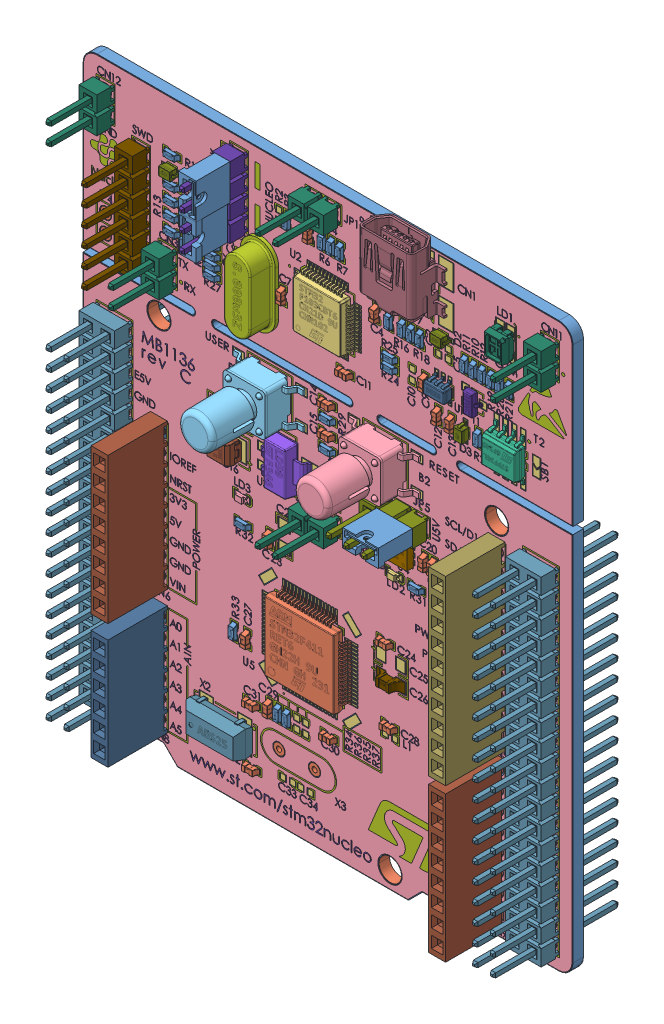
SolidWorks assembly NUCLEO-F411RE.STEP, configuration Défaut. Lengths in mm.
Overall size (70 83.97 20.27).
104 component instances, 40 part files, 0 mates.
Components (placement in the parent):
- NUCLEO-F411RE_PCB_Varsay_lan.STEP-1: NUCLEO-F411RE_PCB_Varsay_lan.STEP [Défaut] at origin size (70 82.5 1.5)
- NUCLEO-F411RE_PCB_HOLEs_Varsay_lan.STEP-1: NUCLEO-F411RE_PCB_HOLEs_Varsay_lan.STEP [Défaut] at origin size (65.28 79.87 1.57)
- NUCLEO-F411RE_PCB_TOP_Pads_Varsay_lan.STEP-1: NUCLEO-F411RE_PCB_TOP_Pads_Varsay_lan.STEP [Défaut] at origin size (59.94 77.1 0.04)
- NUCLEO-F411RE_PCB_TOP_Solder_Varsay_lan.STEP-1: NUCLEO-F411RE_PCB_TOP_Solder_Varsay_lan.STEP [Défaut] at origin size (69.8 82.3 0.05)
- NUCLEO-F411RE_PCB_BOTTOM_Pads_Varsay_lan.STEP-1: NUCLEO-F411RE_PCB_BOTTOM_Pads_Varsay_lan.STEP [Défaut] at origin size (31.1 70.87 0.04)
- NUCLEO-F411RE_PCB_BOTTOM_Solder_Varsay_lan.STEP-1: NUCLEO-F411RE_PCB_BOTTOM_Solder_Varsay_lan.STEP [Défaut] at origin size (69.8 82.3 0.04)
- NUCLEO-F411RE_PCB_TOP_Overlay_Varsay_lan.STEP-1: NUCLEO-F411RE_PCB_TOP_Overlay_Varsay_lan.STEP [Défaut] at origin size (68.09 77.67 0)
- NUCLEO-F411RE_PCB_TOP_Designators_Varsay_lan.STEP-1: NUCLEO-F411RE_PCB_TOP_Designators_Varsay_lan.STEP [Défaut] at origin size (66.29 79.64 0)
- NUCLEO-F411RE_PCB_BOTTOM_Overlay_Varsay_lan.STEP-1: NUCLEO-F411RE_PCB_BOTTOM_Overlay_Varsay_lan.STEP [Défaut] at origin size (40.11 80.77 0)
- SAMTEC_SSQ-106-01-G-S_for_NUCLEO_Varsay_lan.STEP-1: SAMTEC_SSQ-106-01-G-S_for_NUCLEO_Varsay_lan.STEP [Défaut] at (-33.02 8.89 0.785) x (0 1 0) z (1 0 0) size (15.75 11.15 2.41)
- SAMTEC_SSQ-108-01-G-S_for_NUCLEO_Varsay_lan.STEP-1: SAMTEC_SSQ-108-01-G-S_for_NUCLEO_Varsay_lan.STEP [Défaut] at (-33.02 29.21 0.785) x (0 1 0) z (1 0 0) size (20.83 11.15 2.41)
- SAMTEC_SSQ-108-01-G-S_for_NUCLEO_Varsay_lan.STEP-2: SAMTEC_SSQ-108-01-G-S_for_NUCLEO_Varsay_lan.STEP [Défaut] at (15.24 11.43 0.785) x (0 1 0) z (1 0 0) size (20.83 11.15 2.41)
- SAMTEC_SSQ-110-01-G-S_for_NUCLEO_Varsay_lan.STEP-1: SAMTEC_SSQ-110-01-G-S_for_NUCLEO_Varsay_lan.STEP [Défaut] at (15.24 35.814 0.785) x (0 1 0) z (1 0 0) size (25.91 11.15 2.41)
- MOLEX_0678038020_for_NUCLEO.STEP-1: MOLEX_0678038020_for_NUCLEO.STEP [Défaut] at (3.1721 75.2975 0.785) x (-1 0 0) z (0 1 0) size (9.9 4.95 9)
- SAMTEC_TSW-119-07-T-D_for_NUCLEO_Varsay_lan.STEP-1: SAMTEC_TSW-119-07-T-D_for_NUCLEO_Varsay_lan.STEP [Défaut] at (-39.37 25.4 0.785) x (0 -1 0) z (-1 0 0) size (48.26 17.95 5.08)
- SAMTEC_TSW-119-07-T-D_for_NUCLEO_Varsay_lan.STEP-2: SAMTEC_TSW-119-07-T-D_for_NUCLEO_Varsay_lan.STEP [Défaut] at (21.59 25.4 0.785) x (0 -1 0) z (-1 0 0) size (48.26 17.95 5.08)
- SAMTEC_TSW-102-07-T-S_for_NUCLEO_Varsay_lan.STEP-1: SAMTEC_TSW-102-07-T-S_for_NUCLEO_Varsay_lan.STEP [Défaut] at (-40.64 74.93 0.785) x (0 1 0) z (1 0 0) size (5.08 10.92 2.54)
- SAMTEC_TSW-102-07-T-S_for_NUCLEO_Varsay_lan.STEP-2: SAMTEC_TSW-102-07-T-S_for_NUCLEO_Varsay_lan.STEP [Défaut] at (-31.75 59.055 0.785) x (0 -1 0) z (-1 0 0) size (5.08 10.92 2.54)
- SAMTEC_TSW-102-07-T-S_for_NUCLEO_Varsay_lan.STEP-3: SAMTEC_TSW-102-07-T-S_for_NUCLEO_Varsay_lan.STEP [Défaut] at (-9.525 77.47 0.785) x (1 0 0) z (0 -1 0) size (5.08 10.92 2.54)
- SAMTEC_TSW-102-07-T-S_for_NUCLEO_Varsay_lan.STEP-4: SAMTEC_TSW-102-07-T-S_for_NUCLEO_Varsay_lan.STEP [Défaut] at (-9.525 38.735 0.785) x (1 0 0) z (0 -1 0) size (5.08 10.92 2.54)
- SAMTEC_TSW-102-07-T-S_for_NUCLEO_Varsay_lan.STEP-5: SAMTEC_TSW-102-07-T-S_for_NUCLEO_Varsay_lan.STEP [Défaut] at (22.86 74.93 0.785) x (0 -1 0) z (-1 0 0) size (5.08 10.92 2.54)
- SAMTEC_TSW-103-07-T-S_for_NUCLEO_Varsay_lan.STEP-1: SAMTEC_TSW-103-07-T-S_for_NUCLEO_Varsay_lan.STEP [Défaut] at (1.905 45.085 0.785) x (1 0 0) z (0 -1 0) size (7.62 10.92 2.54)
- SAMTEC_TSW-104-07-T-S_for_NUCLEO_Varsay_lan.STEP-1: SAMTEC_TSW-104-07-T-S_for_NUCLEO_Varsay_lan.STEP [Défaut] at (-21.59 73.66 0.785) x (0 1 0) z (1 0 0) size (10.16 10.92 2.54)
- SAMTEC_TSW-106-07-T-S_for_NUCLEO_Varsay_lan.STEP-1: SAMTEC_TSW-106-07-T-S_for_NUCLEO_Varsay_lan.STEP [Défaut] at (-35.56 64.77 0.785) x (0 1 0) z (1 0 0) size (15.24 10.92 2.54)
- MOLEX_90059-0007.STEP-1: MOLEX_90059-0007.STEP [Défaut] at (-21.59 76.2 5.75) x (0 1 0) z (1 0 0) size (5.1 4.85 2.54)
- MOLEX_90059-0007.STEP-2: MOLEX_90059-0007.STEP [Défaut] at (-21.59 71.12 5.75) x (0 -1 0) z (-1 0 0) size (5.1 4.85 2.54)
- ST_STM32F411RET6_Varsay_lan.STEP-1: ST_STM32F411RET6_Varsay_lan.STEP [Défaut] at (-11.4265 21.5935 0.785) x (-1 0 0) z (0 0 -1) size (12 12 1.6)
- ST_STM32F103CBT6_Varsay_lan.STEP-1: ST_STM32F103CBT6_Varsay_lan.STEP [Défaut] at (-8.89 64.77 0.785) x (1 0 0) z (0 -1 0) size (9 1.6 9)
- ESWITCH_TL3301SPF160QGBLK_Varsay_lan.STEP-1: ESWITCH_TL3301SPF160QGBLK_Varsay_lan.STEP [Défaut] at (-0.635 50.8 0.785) x (0 -1 0) z (-1 0 0) size (6 10.7 10)
- ESWITCH_TL3301SPF160QGBLU_Varsay_lan.STEP-1: ESWITCH_TL3301SPF160QGBLU_Varsay_lan.STEP [Défaut] at (-17.145 50.8 0.785) x (0 1 0) z (1 0 0) size (6 10.7 10)
- ST_STS7PF30L_Varsay_lan.STEP-1: ST_STS7PF30L_Varsay_lan.STEP [Défaut] at (17.145 60.325 0.785) x (-1 0 0) z (0 1 0) size (4.9 1.75 6)
- ABRACON_ABL-8.000MHZ-B2_Varsay_lan.STEP-1: ABRACON_ABL-8.000MHZ-B2_Varsay_lan.STEP [Défaut] at (-18.41 63.4908 0.785) x (0 -1 0) z (-1 0 0) size (11.5 5.57 5)
- ST_LD1117S50TR_Varsay_lan.STEP-1: ST_LD1117S50TR_Varsay_lan.STEP [Défaut] at (-14.6685 43.18 0.785) x (0 -1 0) z (-1 0 0) size (6.5 1.9 7)
- ST_LD39050PU33R_Varsay_lan.STEP-1: ST_LD39050PU33R_Varsay_lan.STEP [Défaut] at (1.905 40.64 0.785) x (0 1 0) z (1 0 0) size (3 1 3)
- ST_LD3985M33R_Varsay_lan.STEP-1: ST_LD3985M33R_Varsay_lan.STEP [Défaut] at (7.62 63.5 0.785) x (1 0 0) z (0 -1 0) size (2.95 1.45 2.8)
- KEMET_T491B106K025AT_Varsay_lan.STEP-1: KEMET_T491B106K025AT_Varsay_lan.STEP [Défaut] at (-22.86 41.275 0.785) x (0 -1 0) z (-1 0 0) size (2.8 1.9 3.5)
- ST_STPS2L30A_Varsay_lan.STEP-1: ST_STPS2L30A_Varsay_lan.STEP [Défaut] at (-22.86 45.085 0.785) x (0 1 0) z (1 0 0) size (2.58 2.3 5.07)
- KEMET_T491A106K006AT7280_Varsay_lan.STEP-1: KEMET_T491A106K006AT7280_Varsay_lan.STEP [Défaut] at (-8.255 43.053 0.785) x (1 0 0) z (0 -1 0) size (1.6 1.6 3.2)
- ABRACON_ABS25-32.768KHZ-6-T_Varsay_lan.STEP-1: ABRACON_ABS25-32.768KHZ-6-T_Varsay_lan.STEP [Défaut] at (-23.495 6.35 0.785) x (1 0 0) z (0 -1 0) size (8 2.66 4)
- LUMEX_SML-LX2835IGC-TR.STEP-1: LUMEX_SML-LX2835IGC-TR.STEP [Défaut] at (16.51 73.66 0.785) x (1 0 0) z (0 -1 0) size (2.7 1.8 3.5)
- MOLEX_90059-0007.STEP-3: MOLEX_90059-0007.STEP [Défaut] at (3.175 45.085 5.75) x (-1 0 0) z (0 1 0) size (5.1 4.85 2.54)
- ST_BAT60JFILM_Varsay_lan.STEP-1: ST_BAT60JFILM_Varsay_lan.STEP [Défaut] at (-31.115 71.12 0.785) x (0 -1 0) z (-1 0 0) size (1.28 1.17 2.5)
- ST_BAT60JFILM_Varsay_lan.STEP-2: ST_BAT60JFILM_Varsay_lan.STEP [Défaut] at (7.62 69.85 0.785) x (0 -1 0) z (-1 0 0) size (1.28 1.17 2.5)
- NXP_BC847B,215.STEP-1: NXP_BC847B,215.STEP [Défaut] at (12.065 64.135 0.785) x (0 -1 0) z (-1 0 0) size (2.9 1.1 2.43)
- ST_BAT60JFILM_Varsay_lan.STEP-3: ST_BAT60JFILM_Varsay_lan.STEP [Défaut] at (10.795 59.69 0.785) x (1 0 0) z (0 -1 0) size (1.28 1.17 2.5)
- YAGEO_CC0805KKX7R7BB225.STEP-1: YAGEO_CC0805KKX7R7BB225.STEP [Défaut] at (0.127 23.495 0.785) x (0 -1 0) z (-1 0 0) size (1.58 1.29 4.06)
- YAGEO_RC0603JR-070RL.STEP-1: YAGEO_RC0603JR-070RL.STEP [Défaut] at (17.145 67.945 0.785) x (1 0 0) z (0 -1 0) size (0.8 0.55 2.16)
- YAGEO_RC0603JR-070RL.STEP-2: YAGEO_RC0603JR-070RL.STEP [Défaut] at (15.875 67.945 0.785) x (1 0 0) z (0 -1 0) size (0.8 0.55 2.16)
- YAGEO_RC0603JR-070RL.STEP-3: YAGEO_RC0603JR-070RL.STEP [Défaut] at (14.605 67.945 0.785) x (1 0 0) z (0 -1 0) size (0.8 0.55 2.16)
- YAGEO_RC0603JR-070RL.STEP-4: YAGEO_RC0603JR-070RL.STEP [Défaut] at (13.335 67.945 0.785) x (1 0 0) z (0 -1 0) size (0.8 0.55 2.16)
- YAGEO_RC0603JR-070RL.STEP-5: YAGEO_RC0603JR-070RL.STEP [Défaut] at (12.065 67.945 0.785) x (1 0 0) z (0 -1 0) size (0.8 0.55 2.16)
- YAGEO_RC0603JR-070RL.STEP-6: YAGEO_RC0603JR-070RL.STEP [Défaut] at (10.795 67.945 0.785) x (1 0 0) z (0 -1 0) size (0.8 0.55 2.16)
- YAGEO_RC0603JR-070RL.STEP-7: YAGEO_RC0603JR-070RL.STEP [Défaut] at (12.7 59.7535 0.785) x (1 0 0) z (0 -1 0) size (0.8 0.55 2.16)
- YAGEO_RC0603JR-070RL.STEP-8: YAGEO_RC0603JR-070RL.STEP [Défaut] at (4.445 67.945 0.785) x (1 0 0) z (0 -1 0) size (0.8 0.55 2.16)
- YAGEO_RC0603JR-070RL.STEP-9: YAGEO_RC0603JR-070RL.STEP [Défaut] at (3.175 67.945 0.785) x (1 0 0) z (0 -1 0) size (0.8 0.55 2.16)
- YAGEO_RC0603JR-070RL.STEP-10: YAGEO_RC0603JR-070RL.STEP [Défaut] at (1.905 67.945 0.785) x (1 0 0) z (0 -1 0) size (0.8 0.55 2.16)
- YAGEO_RC0603JR-070RL.STEP-11: YAGEO_RC0603JR-070RL.STEP [Défaut] at (0 67.945 0.785) x (1 0 0) z (0 -1 0) size (0.8 0.55 2.16)
- YAGEO_RC0603JR-070RL.STEP-12: YAGEO_RC0603JR-070RL.STEP [Défaut] at (-6.985 73.025 0.785) x (1 0 0) z (0 -1 0) size (0.8 0.55 2.16)
- YAGEO_RC0603JR-070RL.STEP-13: YAGEO_RC0603JR-070RL.STEP [Défaut] at (-8.255 73.025 0.785) x (1 0 0) z (0 -1 0) size (0.8 0.55 2.16)
- YAGEO_RC0603JR-070RL.STEP-14: YAGEO_RC0603JR-070RL.STEP [Défaut] at (-9.525 73.025 0.785) x (1 0 0) z (0 -1 0) size (0.8 0.55 2.16)
- YAGEO_RC0603JR-070RL.STEP-15: YAGEO_RC0603JR-070RL.STEP [Défaut] at (-14.605 73.025 0.785) x (1 0 0) z (0 -1 0) size (0.8 0.55 2.16)
- YAGEO_RC0603JR-070RL.STEP-16: YAGEO_RC0603JR-070RL.STEP [Défaut] at (-31.115 73.025 0.785) x (0 -1 0) z (-1 0 0) size (0.8 0.55 2.16)
- YAGEO_RC0603JR-070RL.STEP-17: YAGEO_RC0603JR-070RL.STEP [Défaut] at (-31.115 69.215 0.785) x (0 -1 0) z (-1 0 0) size (0.8 0.55 2.16)
- YAGEO_RC0603JR-070RL.STEP-18: YAGEO_RC0603JR-070RL.STEP [Défaut] at (-31.115 67.31 0.785) x (0 -1 0) z (-1 0 0) size (0.8 0.55 2.16)
- YAGEO_RC0603JR-070RL.STEP-19: YAGEO_RC0603JR-070RL.STEP [Défaut] at (-31.115 65.405 0.785) x (0 -1 0) z (-1 0 0) size (0.8 0.55 2.16)
- YAGEO_RC0603JR-070RL.STEP-20: YAGEO_RC0603JR-070RL.STEP [Défaut] at (-31.115 63.5 0.785) x (0 -1 0) z (-1 0 0) size (0.8 0.55 2.16)
- YAGEO_RC0603JR-070RL.STEP-21: YAGEO_RC0603JR-070RL.STEP [Défaut] at (-25.4 64.77 0.785) x (0 -1 0) z (-1 0 0) size (0.8 0.55 2.16)
- YAGEO_RC0603JR-070RL.STEP-22: YAGEO_RC0603JR-070RL.STEP [Défaut] at (-25.4 63.5 0.785) x (0 -1 0) z (-1 0 0) size (0.8 0.55 2.16)
- YAGEO_RC0603JR-070RL.STEP-23: YAGEO_RC0603JR-070RL.STEP [Défaut] at (-25.4 62.23 0.785) x (0 -1 0) z (-1 0 0) size (0.8 0.55 2.16)
- YAGEO_RC0603JR-070RL.STEP-24: YAGEO_RC0603JR-070RL.STEP [Défaut] at (-25.4 60.96 0.785) x (0 -1 0) z (-1 0 0) size (0.8 0.55 2.16)
- YAGEO_RC0603JR-070RL.STEP-25: YAGEO_RC0603JR-070RL.STEP [Défaut] at (-15.875 11.43 0.785) x (1 0 0) z (0 -1 0) size (0.8 0.55 2.16)
- YAGEO_RC0603JR-070RL.STEP-26: YAGEO_RC0603JR-070RL.STEP [Défaut] at (-14.605 11.43 0.785) x (1 0 0) z (0 -1 0) size (0.8 0.55 2.16)
- YAGEO_RC0603JR-070RL.STEP-27: YAGEO_RC0603JR-070RL.STEP [Défaut] at (-22.225 18.415 0.785) x (1 0 0) z (0 -1 0) size (0.8 0.55 2.16)
- YAGEO_RC0603JR-070RL.STEP-28: YAGEO_RC0603JR-070RL.STEP [Défaut] at (-20.955 32.385 0.785) x (0 -1 0) z (-1 0 0) size (0.8 0.55 2.16)
- YAGEO_RC0603JR-070RL.STEP-29: YAGEO_RC0603JR-070RL.STEP [Défaut] at (-8.89 51.435 0.785) x (0 -1 0) z (-1 0 0) size (0.8 0.55 2.16)
- YAGEO_RC0603JR-070RL.STEP-30: YAGEO_RC0603JR-070RL.STEP [Défaut] at (-8.89 47.625 0.785) x (0 -1 0) z (-1 0 0) size (0.8 0.55 2.16)
- YAGEO_RC0603JR-070RL.STEP-31: YAGEO_RC0603JR-070RL.STEP [Défaut] at (3.81 36.83 0.785) x (0 -1 0) z (-1 0 0) size (0.8 0.55 2.16)
- YAGEO_RC0603JR-070RL.STEP-32: YAGEO_RC0603JR-070RL.STEP [Défaut] at (0 63.5 0.785) x (0 -1 0) z (-1 0 0) size (0.8 0.55 2.16)
- YAGEO_RC0603JR-070RL.STEP-33: YAGEO_RC0603JR-070RL.STEP [Défaut] at (0 62.23 0.785) x (0 -1 0) z (-1 0 0) size (0.8 0.55 2.16)
- YAGEO_CC0603KRX7R7BB104.STEP-1: YAGEO_CC0603KRX7R7BB104.STEP [Défaut] at (-11.43 73.025 0.785) x (1 0 0) z (0 -1 0) size (0.8 0.8 2.16)
- YAGEO_CC0603KRX7R7BB104.STEP-2: YAGEO_CC0603KRX7R7BB104.STEP [Défaut] at (-1.905 67.945 0.785) x (1 0 0) z (0 -1 0) size (0.8 0.8 2.16)
- YAGEO_CC0603KRX7R7BB104.STEP-3: YAGEO_CC0603KRX7R7BB104.STEP [Défaut] at (5.08 62.865 0.785) x (1 0 0) z (0 -1 0) size (0.8 0.8 2.16)
- YAGEO_CC0603KRX7R7BB104.STEP-4: YAGEO_CC0603KRX7R7BB104.STEP [Défaut] at (6.985 59.69 0.785) x (1 0 0) z (0 -1 0) size (0.8 0.8 2.16)
- YAGEO_CC0603KRX7R7BB104.STEP-5: YAGEO_CC0603KRX7R7BB104.STEP [Défaut] at (8.89 59.69 0.785) x (1 0 0) z (0 -1 0) size (0.8 0.8 2.16)
- YAGEO_CC0603KRX7R7BB104.STEP-6: YAGEO_CC0603KRX7R7BB104.STEP [Défaut] at (-21.59 62.23 0.785) x (1 0 0) z (0 -1 0) size (0.8 0.8 2.16)
- YAGEO_CC0603KRX7R7BB104.STEP-7: YAGEO_CC0603KRX7R7BB104.STEP [Défaut] at (-21.59 64.77 0.785) x (1 0 0) z (0 -1 0) size (0.8 0.8 2.16)
- YAGEO_CC0603KRX7R7BB104.STEP-8: YAGEO_CC0603KRX7R7BB104.STEP [Défaut] at (-15.24 63.5 0.785) x (1 0 0) z (0 -1 0) size (0.8 0.8 2.16)
- YAGEO_CC0603KRX7R7BB104.STEP-9: YAGEO_CC0603KRX7R7BB104.STEP [Défaut] at (-6.35 58.42 0.785) x (0 -1 0) z (-1 0 0) size (0.8 0.8 2.16)
- YAGEO_CC0603KRX7R7BB104.STEP-10: YAGEO_CC0603KRX7R7BB104.STEP [Défaut] at (-8.89 53.34 0.785) x (0 -1 0) z (-1 0 0) size (0.8 0.8 2.16)
- YAGEO_CC0603KRX7R7BB104.STEP-11: YAGEO_CC0603KRX7R7BB104.STEP [Défaut] at (-8.89 49.53 0.785) x (0 -1 0) z (-1 0 0) size (0.8 0.8 2.16)
- YAGEO_CC0603KRX7R7BB104.STEP-12: YAGEO_CC0603KRX7R7BB104.STEP [Défaut] at (-2.54 40.64 0.785) x (1 0 0) z (0 -1 0) size (0.8 0.8 2.16)
- YAGEO_CC0603KRX7R7BB104.STEP-13: YAGEO_CC0603KRX7R7BB104.STEP [Défaut] at (-1.27 40.64 0.785) x (1 0 0) z (0 -1 0) size (0.8 0.8 2.16)
- YAGEO_CC0603KRX7R7BB104.STEP-14: YAGEO_CC0603KRX7R7BB104.STEP [Défaut] at (5.08 40.64 0.785) x (1 0 0) z (0 -1 0) size (0.8 0.8 2.16)
- YAGEO_CC0603KRX7R7BB104.STEP-15: YAGEO_CC0603KRX7R7BB104.STEP [Défaut] at (6.35 40.64 0.785) x (1 0 0) z (0 -1 0) size (0.8 0.8 2.16)
- YAGEO_CC0603KRX7R7BB104.STEP-16: YAGEO_CC0603KRX7R7BB104.STEP [Défaut] at (-0.6033 27.94 0.785) x (0 -1 0) z (-1 0 0) size (0.8 0.8 2.16)
- YAGEO_CC0603KRX7R7BB104.STEP-17: YAGEO_CC0603KRX7R7BB104.STEP [Défaut] at (-17.145 32.385 0.785) x (1 0 0) z (0 -1 0) size (0.8 0.8 2.16)
- YAGEO_CC0603KRX7R7BB104.STEP-18: YAGEO_CC0603KRX7R7BB104.STEP [Défaut] at (-20.32 18.415 0.785) x (1 0 0) z (0 -1 0) size (0.8 0.8 2.16)
- YAGEO_CC0603KRX7R7BB104.STEP-19: YAGEO_CC0603KRX7R7BB104.STEP [Défaut] at (-17.145 11.43 0.785) x (1 0 0) z (0 -1 0) size (0.8 0.8 2.16)
- YAGEO_CC0603KRX7R7BB104.STEP-20: YAGEO_CC0603KRX7R7BB104.STEP [Défaut] at (0 17.78 0.785) x (0 -1 0) z (-1 0 0) size (0.8 0.8 2.16)
- YAGEO_CC0603KRX7R7BB104.STEP-21: YAGEO_CC0603KRX7R7BB104.STEP [Défaut] at (-8.636 12.192 0.785) x (0 -1 0) z (-1 0 0) size (0.8 0.8 2.16)
- YAGEO_CC0603KRX7R7BB104.STEP-22: YAGEO_CC0603KRX7R7BB104.STEP [Défaut] at (-19.685 2.794 0.785) x (0 -1 0) z (-1 0 0) size (0.8 0.8 2.16)
- YAGEO_CC0603KRX7R7BB104.STEP-23: YAGEO_CC0603KRX7R7BB104.STEP [Défaut] at (-19.685 10.795 0.785) x (0 -1 0) z (-1 0 0) size (0.8 0.8 2.16)
- LUMEX_SML-LX0603SRW-TR.STEP-1: LUMEX_SML-LX0603SRW-TR.STEP [Défaut] at (0.635 36.83 0.785) x (1 0 0) z (0 -1 0) size (2.17 0.59 0.81)
- LUMEX_SML-LX0603GW-TR.STEP-1: LUMEX_SML-LX0603GW-TR.STEP [Défaut] at (-21.1455 35.5597 0.785) x (1 0 0) z (0 -1 0) size (2.17 0.59 0.81)
